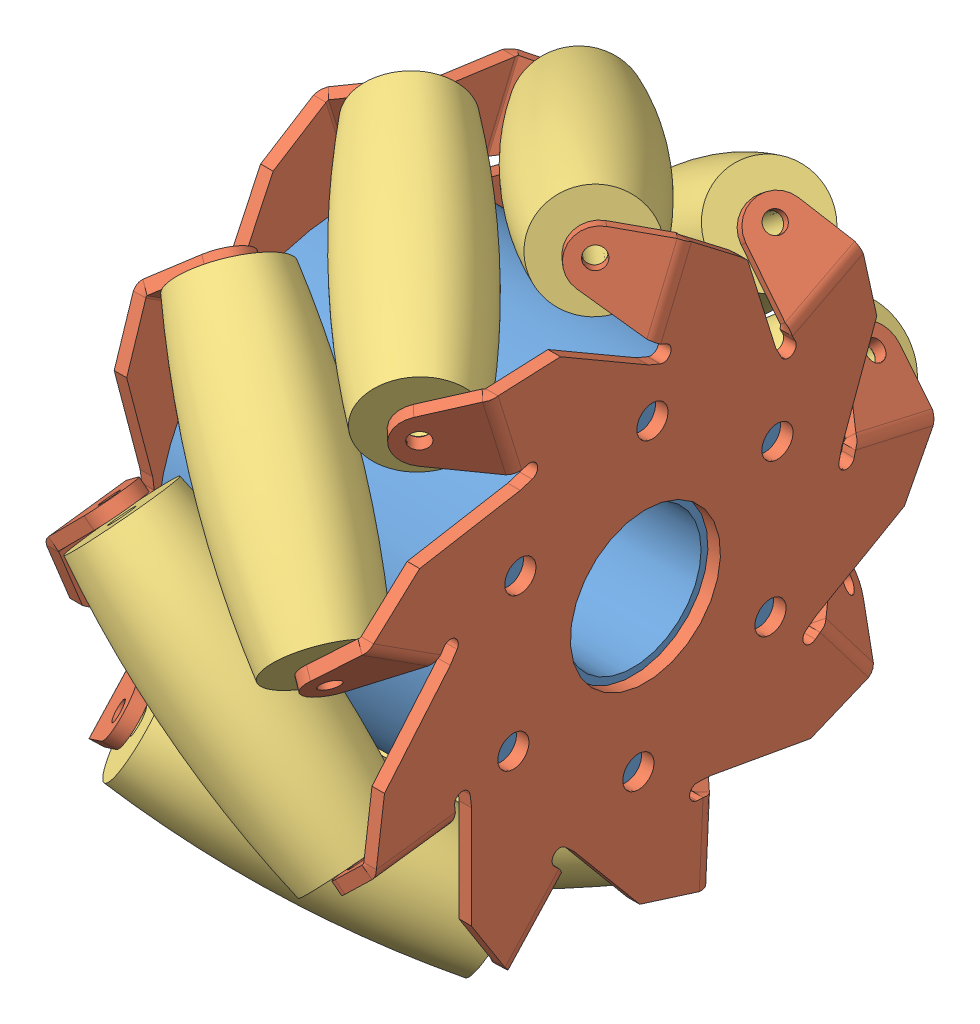
SolidWorks assembly Nexus 100mm Mecanum Wheel Left, configuration Default. Lengths in mm.
Overall size (52.61 130.07 129.92).
12 component instances, 3 part files, 23 mates.
Components (placement in the parent):
- Nexus 100mm Mecanum Wheel Core-1: Nexus 100mm Mecanum Wheel Core [Default] at (-40.8696 21.9785 -5.5023) size (46 60 60)
- Nexus 100mm Mecanum Wheel Left Plate-1: Nexus 100mm Mecanum Wheel Left Plate [Default] at (-40.7988 21.9785 -5.5023) x (0 -0.998889 0.047121) z (0 0.047121 0.998889) size (93.83 10.6 94.33)
- Nexus 100mm Mecanum Wheel Left Plate-2: Nexus 100mm Mecanum Wheel Left Plate [Default] at (5.0597 21.9785 -5.5023) x (0 0.540253 0.841503) z (0 -0.841503 0.540253) size (93.83 10.6 94.33)
- Nexus 100mm Mecanum Wheel Roller-1: Nexus 100mm Mecanum Wheel Roller [Default] at (-17.874 60.4313 6.4785) x (0.701514 0.088758 -0.707107) z (0.707107 -0.210266 0.675121) size (19.45 19.45 47)
- Nexus 100mm Mecanum Wheel Roller-2: Nexus 100mm Mecanum Wheel Roller [Default] at (-17.874 16.8569 34.4468) x (0.541216 0.455066 0.707107) z (-0.707107 0.701377 0.089838) size (19.45 19.45 47)
- Nexus 100mm Mecanum Wheel Roller-3: Nexus 100mm Mecanum Wheel Roller [Default] at (-17.874 43.7339 28.3925) x (0.190917 0.680846 0.707107) z (-0.707107 0.595032 -0.382016) size (19.45 19.45 47)
- Nexus 100mm Mecanum Wheel Roller-4: Nexus 100mm Mecanum Wheel Roller [Default] at (-18.5812 -18.2197 -2.9026) x (-0.702541 0.080226 -0.707107) z (0.707107 -0.03332 -0.706321) size (19.45 19.45 47)
- Nexus 100mm Mecanum Wheel Roller-5: Nexus 100mm Mecanum Wheel Roller [Default] at (-18.5812 -10.4862 -29.3498) x (-0.142834 -0.692531 -0.707107) z (0.707107 0.42849 -0.562491) size (19.45 19.45 47)
- Nexus 100mm Mecanum Wheel Roller-6: Nexus 100mm Mecanum Wheel Roller [Default] at (-17.874 -7.6236 21.8084) x (0.692288 0.619154 0.370655) z (0.707107 -0.479539 -0.519656) size (19.45 19.45 47)
- Nexus 100mm Mecanum Wheel Roller-7: Nexus 100mm Mecanum Wheel Roller [Default] at (-17.874 59.1362 -21.0415) x (0.697397 -0.116781 -0.707107) z (0.707107 0.272886 0.652329) size (19.45 19.45 47)
- Nexus 100mm Mecanum Wheel Roller-8: Nexus 100mm Mecanum Wheel Roller [Default] at (-17.874 40.4545 -41.2905) x (0.622443 -0.335506 -0.707107) z (0.707107 0.628352 0.324305) size (19.45 19.45 47)
- Nexus 100mm Mecanum Wheel Roller-9: Nexus 100mm Mecanum Wheel Roller [Default] at (-17.874 13.1277 -44.7939) x (-0.663165 0.570642 -0.484335) z (0.707107 0.689805 -0.155465) size (19.45 19.45 47)
Mates (geometry in assembly coordinates):
- Concentric1: concentric anti-aligned: circle of Nexus 100mm Mecanum Wheel Core-1; circle of Nexus 100mm Mecanum Wheel Left Plate-2
- Coincident1: coincident anti-aligned: plane of Nexus 100mm Mecanum Wheel Core-1 through (5.1304 21.9785 -5.5023) normal (1 0 0); plane of Nexus 100mm Mecanum Wheel Left Plate-2 through (5.1304 14.9552 -16.4419) normal (-1 0 0)
- Concentric2: concentric aligned: circle of Nexus 100mm Mecanum Wheel Core-1; circle of Nexus 100mm Mecanum Wheel Left Plate-1
- Coincident2: coincident anti-aligned: plane of Nexus 100mm Mecanum Wheel Core-1 through (-40.8696 21.9785 -5.5023) normal (-1 0 0); plane of Nexus 100mm Mecanum Wheel Left Plate-1 through (-40.8696 34.964 -6.1149) normal (1 0 0)
- Concentric3: concentric anti-aligned: circle of Nexus 100mm Mecanum Wheel Left Plate-1; circle of Nexus 100mm Mecanum Wheel Left Plate-2
- Distance1: distance = 0.5 mm anti-aligned: plane of Nexus 100mm Mecanum Wheel Left Plate-1 through (-41.4553 65.0771 -2.9253) normal (0.707107 -0.210266 0.675121); plane of Nexus 100mm Mecanum Wheel Roller-1 through (-34.4911 65.3726 -9.3869) normal (-0.707107 0.210266 -0.675121)
- Concentric4: concentric anti-aligned: circle of Nexus 100mm Mecanum Wheel Left Plate-1; circle of Nexus 100mm Mecanum Wheel Roller-1
- Distance2: distance = 0.5 mm anti-aligned: plane of Nexus 100mm Mecanum Wheel Roller-7 through (-34.4911 52.7233 -36.3712) normal (-0.707107 -0.272886 -0.652329); plane of Nexus 100mm Mecanum Wheel Left Plate-1 through (-41.4553 56.6504 -31.2314) normal (0.707107 0.272886 0.652329)
- Distance3: distance = 0.5 mm anti-aligned: plane of Nexus 100mm Mecanum Wheel Roller-8 through (-34.4911 25.6883 -48.9117) normal (-0.707107 -0.628352 -0.324305); plane of Nexus 100mm Mecanum Wheel Left Plate-1 through (-41.4553 32.0004 -47.4986) normal (0.707107 0.628352 0.324305)
- Distance4: distance = 0.5 mm anti-aligned: plane of Nexus 100mm Mecanum Wheel Roller-9 through (-34.4911 -3.0827 -41.1404) normal (-0.707107 -0.689805 0.155465); plane of Nexus 100mm Mecanum Wheel Left Plate-1 through (-41.4553 2.661 -44.1153) normal (0.707107 0.689805 -0.155465)
- Distance5: distance = 0.5 mm anti-aligned: plane of Nexus 100mm Mecanum Wheel Roller-5 through (-35.1982 -20.5557 -16.1312) normal (-0.707107 -0.42849 0.562491); plane of Nexus 100mm Mecanum Wheel Left Plate-1 through (-41.4553 -17.6395 -22.6646) normal (0.707107 0.42849 -0.562491)
- Distance6: distance = 0.5 mm anti-aligned: plane of Nexus 100mm Mecanum Wheel Left Plate-1 through (-41.4553 -19.4024 6.8166) normal (0.707107 -0.03332 -0.706321); plane of Nexus 100mm Mecanum Wheel Roller-4 through (-35.1982 -17.4367 13.6959) normal (-0.707107 0.03332 0.706321)
- Concentric5: concentric anti-aligned: circle of Nexus 100mm Mecanum Wheel Left Plate-1; circle of Nexus 100mm Mecanum Wheel Roller-4
- Concentric6: concentric anti-aligned: circle of Nexus 100mm Mecanum Wheel Left Plate-1; circle of Nexus 100mm Mecanum Wheel Roller-5
- Concentric7: concentric anti-aligned: circle of Nexus 100mm Mecanum Wheel Left Plate-1; circle of Nexus 100mm Mecanum Wheel Roller-8
- Concentric8: concentric anti-aligned: circle of Nexus 100mm Mecanum Wheel Left Plate-1; cylinder of Nexus 100mm Mecanum Wheel Roller-9 through (-34.4911 -3.0827 -41.1404) axis (0.707107 0.689805 -0.155465) radius 2
- Concentric9: concentric anti-aligned: circle of Nexus 100mm Mecanum Wheel Left Plate-1; cylinder of Nexus 100mm Mecanum Wheel Roller-7 through (-34.4911 52.7233 -36.3712) axis (0.707107 0.272886 0.652329) radius 2
- Concentric10: concentric anti-aligned: circle of Nexus 100mm Mecanum Wheel Left Plate-1; circle of Nexus 100mm Mecanum Wheel Roller-6
- Distance7: distance = 0.5 mm anti-aligned: plane of Nexus 100mm Mecanum Wheel Roller-6 through (-34.4911 3.6455 34.0203) normal (-0.707107 0.479539 0.519656); plane of Nexus 100mm Mecanum Wheel Left Plate-1 through (-41.4553 -1.8026 30.5336) normal (0.707107 -0.479539 -0.519656)
- Distance8: distance = 0.5 mm anti-aligned: plane of Nexus 100mm Mecanum Wheel Roller-2 through (-34.4911 33.3393 36.558) normal (-0.707107 0.701377 0.089838); plane of Nexus 100mm Mecanum Wheel Left Plate-1 through (-41.4553 26.9246 37.389) normal (0.707107 -0.701377 -0.089838)
- Concentric11: concentric aligned: circle of Nexus 100mm Mecanum Wheel Left Plate-1; circle of Nexus 100mm Mecanum Wheel Roller-2
- Distance9: distance = 0.5 mm anti-aligned: plane of Nexus 100mm Mecanum Wheel Roller-3 through (-34.4911 57.7172 19.4151) normal (-0.707107 0.595032 -0.382016); plane of Nexus 100mm Mecanum Wheel Left Plate-1 through (-41.4553 53.3374 24.175) normal (0.707107 -0.595032 0.382016)
- Concentric12: concentric aligned: circle of Nexus 100mm Mecanum Wheel Left Plate-1; circle of Nexus 100mm Mecanum Wheel Roller-3
